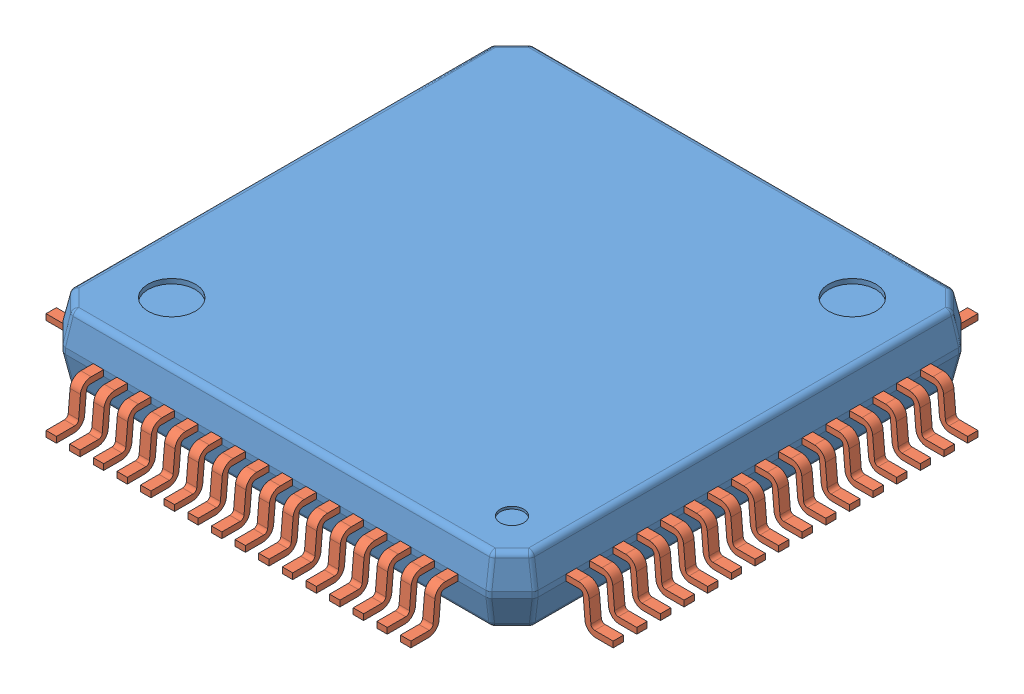
SolidWorks assembly PM0064A, configuration Default. Lengths in mm.
Overall size (12 1.52 12).
65 component instances, 2 part files, 0 mates.
Components (placement in the parent):
- BODY_VEH64A-1: BODY_VEH64A [Default] at (0 0.125 0) x (0 0 -1) z (1 0 0) size (10 1.46 10)
- LEAD_VEH64A-1: LEAD_VEH64A [Default] at (-3.75 -0.475 5.4) size (0.22 0.85 1)
- LEAD_VEH64A-2: LEAD_VEH64A [Default] at (-3.25 -0.475 5.4) size (0.22 0.85 1)
- LEAD_VEH64A-3: LEAD_VEH64A [Default] at (-2.75 -0.475 5.4) size (0.22 0.85 1)
- LEAD_VEH64A-4: LEAD_VEH64A [Default] at (-2.25 -0.475 5.4) size (0.22 0.85 1)
- LEAD_VEH64A-5: LEAD_VEH64A [Default] at (-1.75 -0.475 5.4) size (0.22 0.85 1)
- LEAD_VEH64A-6: LEAD_VEH64A [Default] at (-1.25 -0.475 5.4) size (0.22 0.85 1)
- LEAD_VEH64A-7: LEAD_VEH64A [Default] at (-0.75 -0.475 5.4) size (0.22 0.85 1)
- LEAD_VEH64A-8: LEAD_VEH64A [Default] at (-0.25 -0.475 5.4) size (0.22 0.85 1)
- LEAD_VEH64A-9: LEAD_VEH64A [Default] at (0.25 -0.475 5.4) size (0.22 0.85 1)
- LEAD_VEH64A-10: LEAD_VEH64A [Default] at (0.75 -0.475 5.4) size (0.22 0.85 1)
- LEAD_VEH64A-11: LEAD_VEH64A [Default] at (1.25 -0.475 5.4) size (0.22 0.85 1)
- LEAD_VEH64A-12: LEAD_VEH64A [Default] at (1.75 -0.475 5.4) size (0.22 0.85 1)
- LEAD_VEH64A-13: LEAD_VEH64A [Default] at (2.25 -0.475 5.4) size (0.22 0.85 1)
- LEAD_VEH64A-14: LEAD_VEH64A [Default] at (2.75 -0.475 5.4) size (0.22 0.85 1)
- LEAD_VEH64A-15: LEAD_VEH64A [Default] at (3.25 -0.475 5.4) size (0.22 0.85 1)
- LEAD_VEH64A-16: LEAD_VEH64A [Default] at (3.75 -0.475 5.4) size (0.22 0.85 1)
- LEAD_VEH64A-17: LEAD_VEH64A [Default] at (5.4 -0.475 3.75) x (0 0 -1) z (1 0 0) size (0.22 0.85 1)
- LEAD_VEH64A-18: LEAD_VEH64A [Default] at (5.4 -0.475 3.25) x (0 0 -1) z (1 0 0) size (0.22 0.85 1)
- LEAD_VEH64A-19: LEAD_VEH64A [Default] at (5.4 -0.475 2.75) x (0 0 -1) z (1 0 0) size (0.22 0.85 1)
- LEAD_VEH64A-20: LEAD_VEH64A [Default] at (5.4 -0.475 2.25) x (0 0 -1) z (1 0 0) size (0.22 0.85 1)
- LEAD_VEH64A-21: LEAD_VEH64A [Default] at (5.4 -0.475 1.75) x (0 0 -1) z (1 0 0) size (0.22 0.85 1)
- LEAD_VEH64A-22: LEAD_VEH64A [Default] at (5.4 -0.475 1.25) x (0 0 -1) z (1 0 0) size (0.22 0.85 1)
- LEAD_VEH64A-23: LEAD_VEH64A [Default] at (5.4 -0.475 0.75) x (0 0 -1) z (1 0 0) size (0.22 0.85 1)
- LEAD_VEH64A-24: LEAD_VEH64A [Default] at (5.4 -0.475 0.25) x (0 0 -1) z (1 0 0) size (0.22 0.85 1)
- LEAD_VEH64A-25: LEAD_VEH64A [Default] at (5.4 -0.475 -0.25) x (0 0 -1) z (1 0 0) size (0.22 0.85 1)
- LEAD_VEH64A-26: LEAD_VEH64A [Default] at (5.4 -0.475 -0.75) x (0 0 -1) z (1 0 0) size (0.22 0.85 1)
- LEAD_VEH64A-27: LEAD_VEH64A [Default] at (5.4 -0.475 -1.25) x (0 0 -1) z (1 0 0) size (0.22 0.85 1)
- LEAD_VEH64A-28: LEAD_VEH64A [Default] at (5.4 -0.475 -1.75) x (0 0 -1) z (1 0 0) size (0.22 0.85 1)
- LEAD_VEH64A-29: LEAD_VEH64A [Default] at (5.4 -0.475 -2.25) x (0 0 -1) z (1 0 0) size (0.22 0.85 1)
- LEAD_VEH64A-30: LEAD_VEH64A [Default] at (5.4 -0.475 -2.75) x (0 0 -1) z (1 0 0) size (0.22 0.85 1)
- LEAD_VEH64A-31: LEAD_VEH64A [Default] at (5.4 -0.475 -3.25) x (0 0 -1) z (1 0 0) size (0.22 0.85 1)
- LEAD_VEH64A-32: LEAD_VEH64A [Default] at (5.4 -0.475 -3.75) x (0 0 -1) z (1 0 0) size (0.22 0.85 1)
- LEAD_VEH64A-33: LEAD_VEH64A [Default] at (3.75 -0.475 -5.4) x (-1 0 0) z (0 0 -1) size (0.22 0.85 1)
- LEAD_VEH64A-34: LEAD_VEH64A [Default] at (3.25 -0.475 -5.4) x (-1 0 0) z (0 0 -1) size (0.22 0.85 1)
- LEAD_VEH64A-35: LEAD_VEH64A [Default] at (2.75 -0.475 -5.4) x (-1 0 0) z (0 0 -1) size (0.22 0.85 1)
- LEAD_VEH64A-36: LEAD_VEH64A [Default] at (2.25 -0.475 -5.4) x (-1 0 0) z (0 0 -1) size (0.22 0.85 1)
- LEAD_VEH64A-37: LEAD_VEH64A [Default] at (1.75 -0.475 -5.4) x (-1 0 0) z (0 0 -1) size (0.22 0.85 1)
- LEAD_VEH64A-38: LEAD_VEH64A [Default] at (1.25 -0.475 -5.4) x (-1 0 0) z (0 0 -1) size (0.22 0.85 1)
- LEAD_VEH64A-39: LEAD_VEH64A [Default] at (0.75 -0.475 -5.4) x (-1 0 0) z (0 0 -1) size (0.22 0.85 1)
- LEAD_VEH64A-40: LEAD_VEH64A [Default] at (0.25 -0.475 -5.4) x (-1 0 0) z (0 0 -1) size (0.22 0.85 1)
- LEAD_VEH64A-41: LEAD_VEH64A [Default] at (-0.25 -0.475 -5.4) x (-1 0 0) z (0 0 -1) size (0.22 0.85 1)
- LEAD_VEH64A-42: LEAD_VEH64A [Default] at (-0.75 -0.475 -5.4) x (-1 0 0) z (0 0 -1) size (0.22 0.85 1)
- LEAD_VEH64A-43: LEAD_VEH64A [Default] at (-1.25 -0.475 -5.4) x (-1 0 0) z (0 0 -1) size (0.22 0.85 1)
- LEAD_VEH64A-44: LEAD_VEH64A [Default] at (-1.75 -0.475 -5.4) x (-1 0 0) z (0 0 -1) size (0.22 0.85 1)
- LEAD_VEH64A-45: LEAD_VEH64A [Default] at (-2.25 -0.475 -5.4) x (-1 0 0) z (0 0 -1) size (0.22 0.85 1)
- LEAD_VEH64A-46: LEAD_VEH64A [Default] at (-2.75 -0.475 -5.4) x (-1 0 0) z (0 0 -1) size (0.22 0.85 1)
- LEAD_VEH64A-47: LEAD_VEH64A [Default] at (-3.25 -0.475 -5.4) x (-1 0 0) z (0 0 -1) size (0.22 0.85 1)
- LEAD_VEH64A-48: LEAD_VEH64A [Default] at (-3.75 -0.475 -5.4) x (-1 0 0) z (0 0 -1) size (0.22 0.85 1)
- LEAD_VEH64A-49: LEAD_VEH64A [Default] at (-5.4 -0.475 -3.75) x (0 0 1) z (-1 0 0) size (0.22 0.85 1)
- LEAD_VEH64A-50: LEAD_VEH64A [Default] at (-5.4 -0.475 -3.25) x (0 0 1) z (-1 0 0) size (0.22 0.85 1)
- LEAD_VEH64A-51: LEAD_VEH64A [Default] at (-5.4 -0.475 -2.75) x (0 0 1) z (-1 0 0) size (0.22 0.85 1)
- LEAD_VEH64A-52: LEAD_VEH64A [Default] at (-5.4 -0.475 -2.25) x (0 0 1) z (-1 0 0) size (0.22 0.85 1)
- LEAD_VEH64A-53: LEAD_VEH64A [Default] at (-5.4 -0.475 -1.75) x (0 0 1) z (-1 0 0) size (0.22 0.85 1)
- LEAD_VEH64A-54: LEAD_VEH64A [Default] at (-5.4 -0.475 -1.25) x (0 0 1) z (-1 0 0) size (0.22 0.85 1)
- LEAD_VEH64A-55: LEAD_VEH64A [Default] at (-5.4 -0.475 -0.75) x (0 0 1) z (-1 0 0) size (0.22 0.85 1)
- LEAD_VEH64A-56: LEAD_VEH64A [Default] at (-5.4 -0.475 -0.25) x (0 0 1) z (-1 0 0) size (0.22 0.85 1)
- LEAD_VEH64A-57: LEAD_VEH64A [Default] at (-5.4 -0.475 0.25) x (0 0 1) z (-1 0 0) size (0.22 0.85 1)
- LEAD_VEH64A-58: LEAD_VEH64A [Default] at (-5.4 -0.475 0.75) x (0 0 1) z (-1 0 0) size (0.22 0.85 1)
- LEAD_VEH64A-59: LEAD_VEH64A [Default] at (-5.4 -0.475 1.25) x (0 0 1) z (-1 0 0) size (0.22 0.85 1)
- LEAD_VEH64A-60: LEAD_VEH64A [Default] at (-5.4 -0.475 1.75) x (0 0 1) z (-1 0 0) size (0.22 0.85 1)
- LEAD_VEH64A-61: LEAD_VEH64A [Default] at (-5.4 -0.475 2.25) x (0 0 1) z (-1 0 0) size (0.22 0.85 1)
- LEAD_VEH64A-62: LEAD_VEH64A [Default] at (-5.4 -0.475 2.75) x (0 0 1) z (-1 0 0) size (0.22 0.85 1)
- LEAD_VEH64A-63: LEAD_VEH64A [Default] at (-5.4 -0.475 3.25) x (0 0 1) z (-1 0 0) size (0.22 0.85 1)
- LEAD_VEH64A-64: LEAD_VEH64A [Default] at (-5.4 -0.475 3.75) x (0 0 1) z (-1 0 0) size (0.22 0.85 1)
